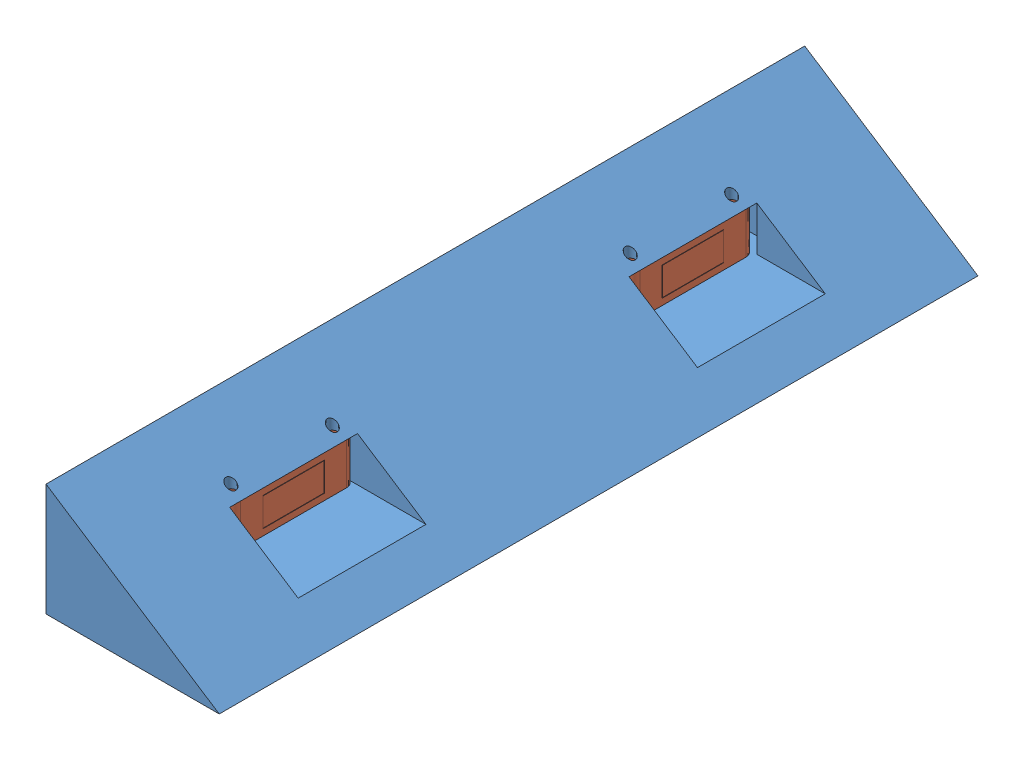
SolidWorks assembly Sensores_front, configuration Predeterminado. Lengths in mm.
Overall size (51.37 28.17 190).
7 component instances, 3 part files, 8 mates.
Components (placement in the parent):
- soporte_sensores_front-1: soporte_sensores_front [Predeterminado] at (-28.062 -12.5853 95) size (43.38 28.17 190)
- OMRON-E3Z-D62_D82-1: OMRON-E3Z-D62_D82 [Predeterminado] at (-14.062 2.3454 152.7) x (-1 0 0) z (0 -1 0) size (24.99 38.09 10.8)
- OMRON-E3Z-D62_D82-2: OMRON-E3Z-D62_D82 [Predeterminado] at (-14.062 2.3454 227.3) x (-1 0 0) z (0 1 0) size (24.99 38.09 10.8)
- Tornillo M3x15-1: Tornillo M3x15 [Predeterminado] at (-14.062 5.4147 127.3) x (1 0 0) z (0 -1 0) size (5 5 15.24)
- Tornillo M3x15-2: Tornillo M3x15 [Predeterminado] at (-14.062 5.4147 152.7) x (1 0 0) z (0 -1 0) size (5 5 15.24)
- Tornillo M3x15-3: Tornillo M3x15 [Predeterminado] at (-14.062 5.4147 227.3) x (1 0 0) z (0 -1 0) size (5 5 15.24)
- Tornillo M3x15-4: Tornillo M3x15 [Predeterminado] at (-14.062 5.4147 252.7) x (1 0 0) z (0 -1 0) size (5 5 15.24)
Mates (geometry in assembly coordinates):
- Coincidente13: coincident anti-aligned: line of soporte_sensores_front-1 through (-11.062 7.5454 224) axis (0 0 1); line of OMRON-E3Z-D62_D82-2 through (-11.062 7.5454 253.25) axis (0 0 -1)
- Coincidente14: coincident anti-aligned: line of soporte_sensores_front-1 through (-11.062 7.5454 156) axis (0 0 -1); line of OMRON-E3Z-D62_D82-1 through (-11.062 7.5454 126.75) axis (0 0 1)
- Distancia5: distance = 0.5 mm anti-aligned: plane of OMRON-E3Z-D62_D82-1 through (-31.062 7.5454 124.5) normal (0 0 -1); plane of soporte_sensores_front-1 through (-11.062 7.5454 124) normal (0 0 1)
- Distancia6: distance = 0.5 mm anti-aligned: plane of OMRON-E3Z-D62_D82-2 through (-31.062 -2.8546 255.5) normal (0 0 1); plane of soporte_sensores_front-1 through (-11.062 7.5454 256) normal (0 0 -1)
- Coincidente21: coincident aligned: cone of soporte_sensores_front-1 through (-14.062 -7.5853 252.7) axis (0 1 0); cone of Tornillo M3x15-4 through (-14.062 -9.0853 252.7) axis (0 1 0)
- Coincidente22: coincident aligned: cone of soporte_sensores_front-1 through (-14.062 -7.5853 227.3) axis (0 1 0); cone of Tornillo M3x15-3 through (-14.062 -9.0853 227.3) axis (0 1 0)
- Coincidente23: coincident aligned: cone of soporte_sensores_front-1 through (-14.062 -7.5853 152.7) axis (0 1 0); cone of Tornillo M3x15-2 through (-14.062 -9.0853 152.7) axis (0 1 0)
- Coincidente24: coincident aligned: cone of soporte_sensores_front-1 through (-14.062 -7.5853 127.3) axis (0 1 0); cone of Tornillo M3x15-1 through (-14.062 -9.0853 127.3) axis (0 1 0)
